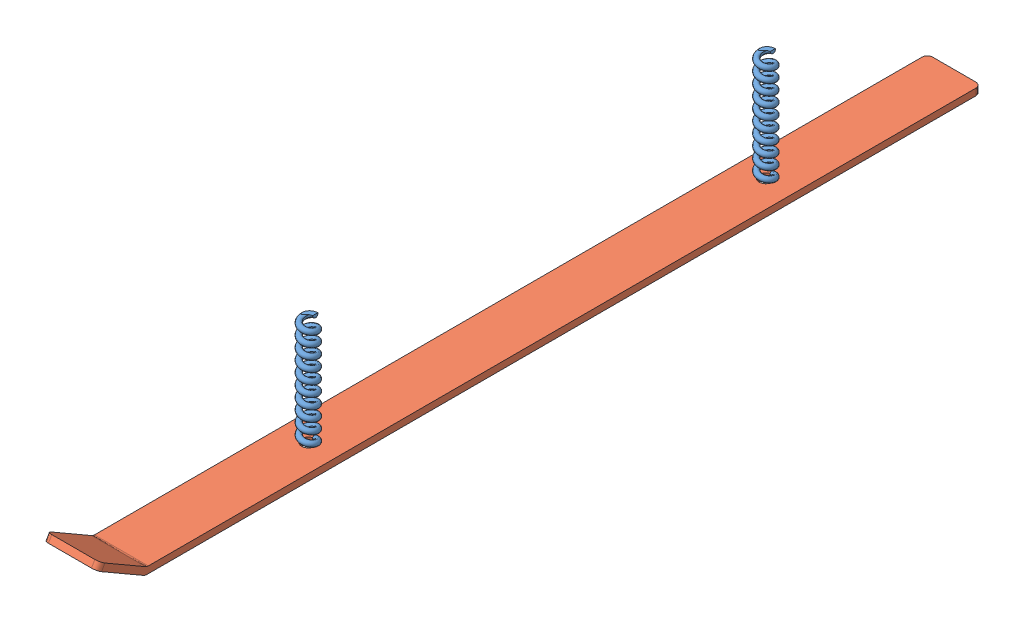
SolidWorks assembly SkidAssembly, configuration Default. Lengths in mm.
Overall size (25.4 56.22 417.28).
3 component instances, 2 part files, 6 mates.
Components (placement in the parent):
- Rudimentary Spring-1: Rudimentary Spring [Default] at (21.385 -21.8607 89.2392) x (0.707107 0 0.707107) z (-0.707107 0 0.707107) size (9.2 55.29 9.2)
- Skid Plate-1: Skid Plate [Default] at (8.685 -21.8607 178.1392) size (25.4 15.88 417.28)
- Rudimentary Spring-2: Rudimentary Spring [Default] at (21.385 -21.8607 -126.6608) x (0.707107 0 0.707107) z (-0.707107 0 0.707107) size (9.2 55.29 9.2)
Mates (geometry in assembly coordinates):
- Coincident1: coincident anti-aligned: plane of Rudimentary Spring-1 through (12.9683 -21.8607 91.148) normal (0 -1 0); plane of Skid Plate-1 through (34.085 -21.8607 178.1392) normal (0 1 0)
- Coincident2: coincident anti-aligned: plane of Skid Plate-1 through (34.085 -21.8607 178.1392) normal (0 1 0); plane of Rudimentary Spring-2 through (12.9683 -21.8607 -124.752) normal (0 -1 0)
- Concentric1: concentric aligned: circle of Skid Plate-1; circle of Rudimentary Spring-2
- Concentric2: concentric aligned: circle of Rudimentary Spring-1; circle of Skid Plate-1
- Parallel1: parallel aligned: line of Rudimentary Spring-1 through (21.385 28.9393 84.7942) axis (0 0 1); line of Rudimentary Spring-2 through (21.385 28.9393 -131.1058) axis (0 0 1)
- Parallel3: parallel aligned: line of Rudimentary Spring-1 through (21.385 28.9393 84.7942) axis (0 0 1); line of Skid Plate-1 through (34.085 -21.8607 -213.0208) axis (0 0 1)
